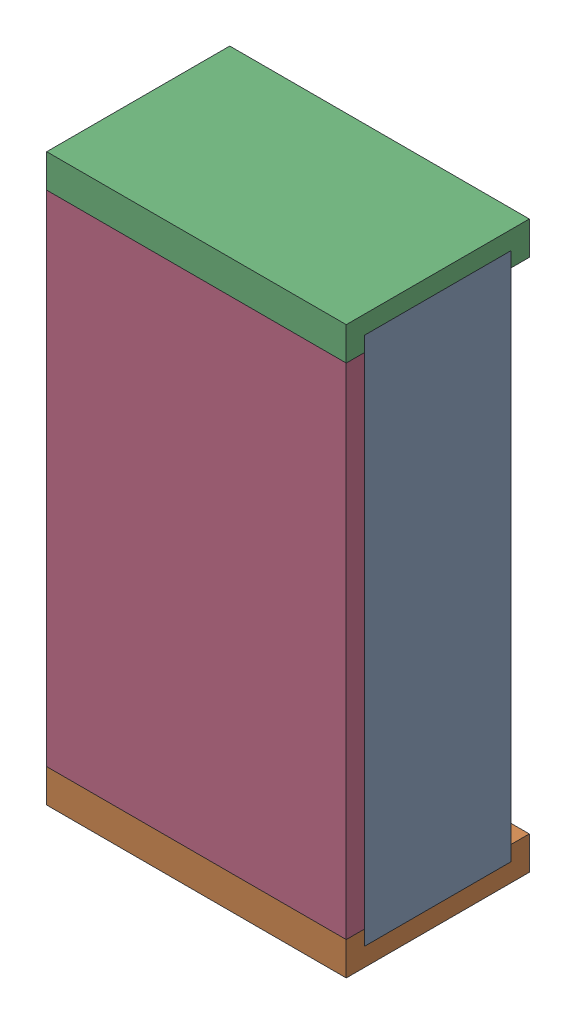
SolidWorks assembly R10, configuration Default. Lengths in mm.
Overall size (0.9 1.7 0.55).
7 component instances, 3 part files, 0 mates.
Components (placement in the parent):
- 6019289040-1: 6019289040 [Default] at (27.1699 2.6671 0) x (0 1 0) z (0 0 1) size (1.7 0.9 0.55)
  - Mid_Body-1: Mid_Body [Default] at (-0.85 -0.45 0) size (1.59 0.9 0.44)
  - Terminal-1: Terminal [Default] at (-0.85 -0.45 0) size (0.1 0.9 0.55)
    - Open CASCADE STEP translator 6.8 15.2.1-1: Open CASCADE STEP translator 6.8 15.2.1 [Default] at origin size (0.1 0.9 0.55)
  - Terminal-2: Terminal [Default] at (0.85 0.45 0) x (-1 0 0) z (0 0 1) size (0.1 0.9 0.55)
    - Open CASCADE STEP translator 6.8 15.2.1-1: Open CASCADE STEP translator 6.8 15.2.1 [Default] at origin size (0.1 0.9 0.55)
  - Mark-1: Mark [Default] at (-0.75 -0.45 0.495) size (1.5 0.9 0.06)
